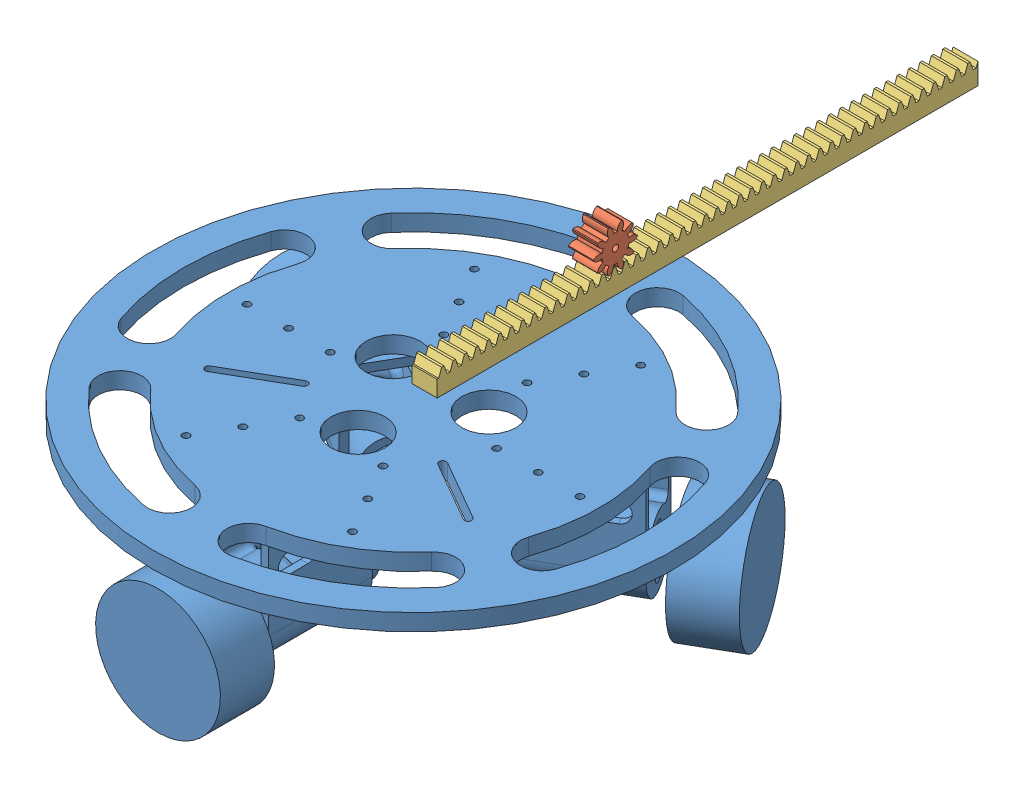
SolidWorks assembly mike_assembly, configuration Default. Lengths in mm.
Overall size (250 106.5 391.67).
3 component instances, 3 part files, 4 mates.
Components (placement in the parent):
- honnun-robot-1: honnun-robot [Default] at (84.2788 -30.9978 208.1719) size (250 76.95 250)
- spur gear_gb-1: spur gear_gb [GB - Spur gear 1.75M 10T 20PA 12FW ---S10A75H50L3.0N] at (77.0124 171.5022 115.7779) size (12 20.11 21)
- rack spur rectangular_am-1: rack spur rectangular_am [Metric - Rack-spur - rectangular 1.75M 20PA 12FW 10PH 260L---SAll] at (89.0124 152.0022 201.5021) x (0 0 -1) z (1 0 0) size (260 11.75 12)
Mates (geometry in assembly coordinates):
- Distance2: distance = 18 mm: cylinder of spur gear_gb-1 through (127.0125 171.5022 115.7779) axis (-1 0 0) radius 1.5; plane of honnun-robot-1 through (84.2788 152.0022 208.1719) normal (0 1 0)
- Coincident6: coincident aligned: plane of spur gear_gb-1 through (77.0124 171.5022 115.7779) normal (-1 0 0); plane of rack spur rectangular_am-1 through (77.0124 163.7522 201.5021) normal (-1 0 0)
- Coincident7: coincident anti-aligned: plane of honnun-robot-1 through (84.2788 152.0022 208.1719) normal (0 1 0); plane of rack spur rectangular_am-1 through (77.0124 152.0022 201.5021) normal (0 -1 0)
- Tangent2: tangent anti-aligned: cylinder of spur gear_gb-1 through (89.0124 164.6183 120.2743) axis (-1 0 0) radius 3.5; plane of rack spur rectangular_am-1 through (77.0124 163.7776 116.8557) normal (0 0.34202 0.939693)
